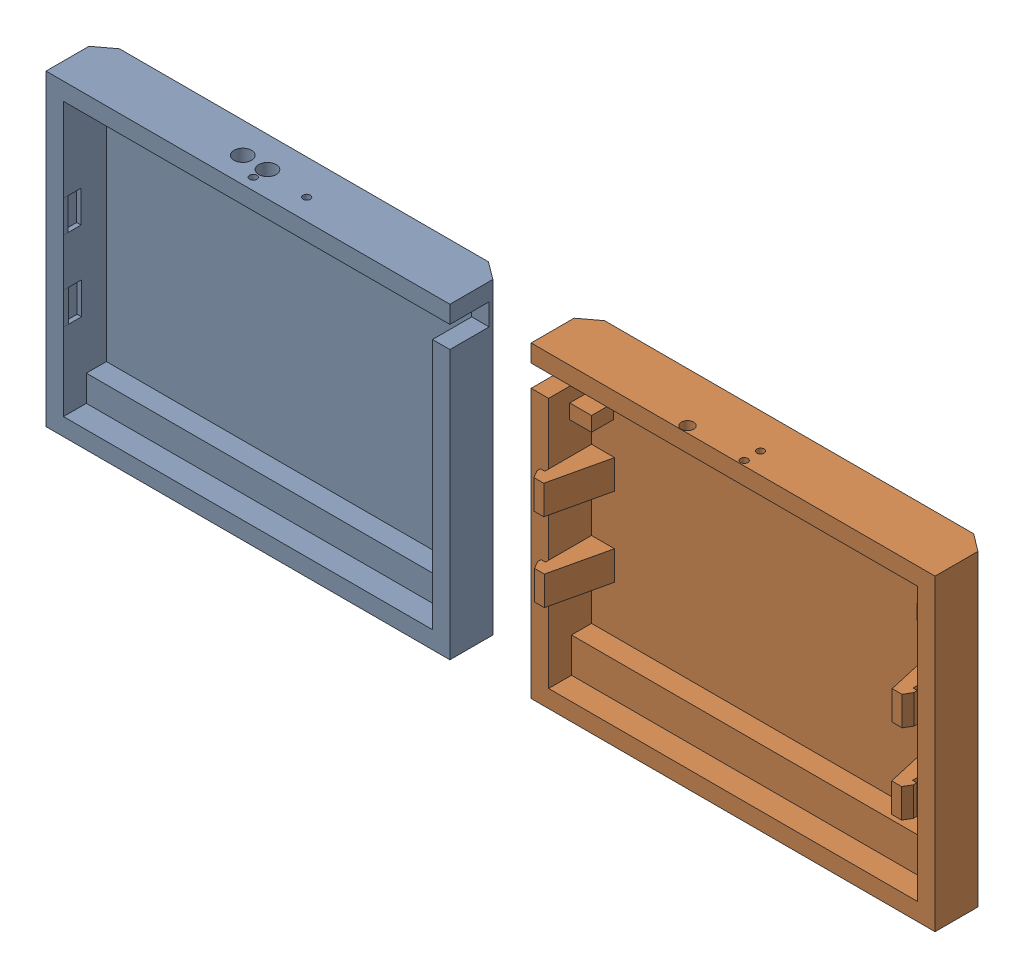
SolidWorks assembly fullShellScaled, configuration Default. Lengths in mm.
Overall size (122.33 43.35 9.91).
2 component instances, 2 part files, 1 mates.
Components (placement in the parent):
- shellHalfGrooveScaled-1: shellHalfGrooveScaled [Default] at (-22.7618 3.5076 33.3672) size (55.57 42.37 7.71)
- shellHalfHookScaled-1: shellHalfHookScaled [Default] at (-15.4102 4.4338 35.5581) size (55.57 42.37 9.91)
Mates (geometry in assembly coordinates):
- Coincident1: coincident aligned: plane of shellHalfGrooveScaled-1 through (2.6489 42.5636 26.5308) normal (0 0 -1); plane of shellHalfHookScaled-1 through (18.6279 43.5406 26.5308) normal (0 0 -1)
